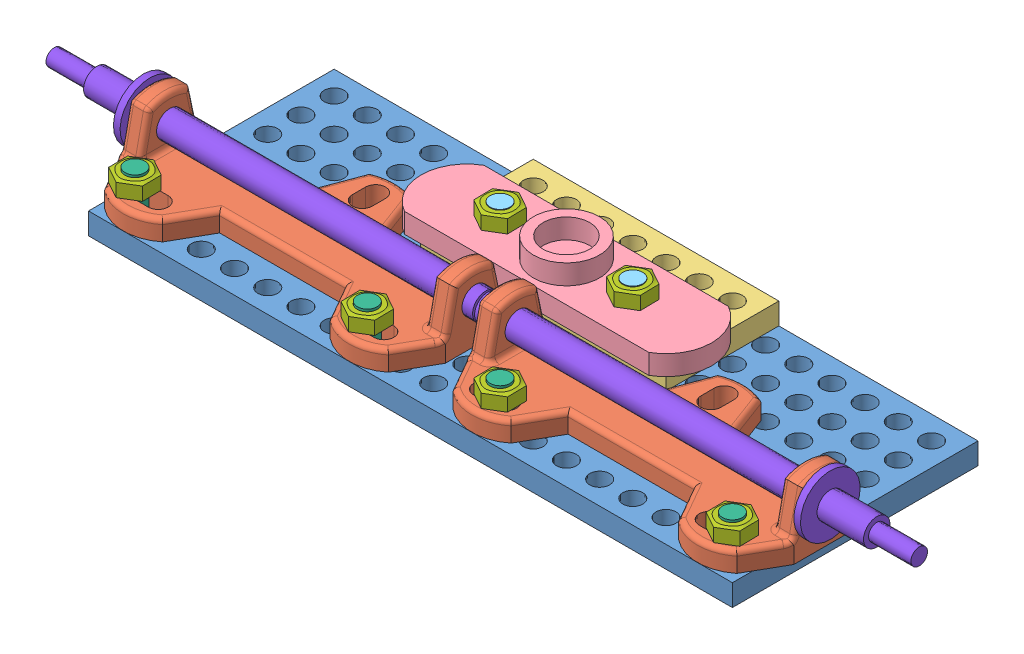
SolidWorks assembly 3, configuration Default. Lengths in mm.
Overall size (130.3 16.9 37).
19 component instances, 8 part files, 61 mates.
Components (placement in the parent):
- 3-0-1-1: 3-0-1 [Default] at (0 -9.5 5) size (97 3.25 37)
- 3-1-1-1: 3-1-1 [Default] at (14.0006 -6.25 11.4978) x (1 0 0.000071) z (-0.000071 0 1) size (49.08 10 24)
- 3-1-1-2: 3-1-1 [Default] at (-38.5006 -6.25 11.4995) x (1 0 -0.000071) z (0.000071 0 1) size (49.08 10 24)
- 3-3-1-1: 3-3-1 [Default] at (0 -6.25 -5) size (37 3.25 17)
- 3-4-1-1: 3-4-1 [Default] at (0 -3 0) size (43.8 6 12)
- 9-4-1-6: 9-4-1 [Default] at (-10 2.5 0) x (-1 0 0) z (0 0 1) size (5 13.48 5)
- 9-4-1-7: 9-4-1 [Default] at (10 2.5 0) x (1 0 0) z (0 0 -1) size (5 13.48 5)
- 9-3-1-10: 9-3-1 [Default] at (10 -0.5 20) x (1 0 0) z (0 0 -1) size (5 10.48 5)
- 9-3-1-11: 9-3-1 [Default] at (45 -0.5 20) x (1 0 0) z (0 0 -1) size (5 10.48 5)
- 9-3-1-12: 9-3-1 [Default] at (-10 -0.5 20) x (-1 0 0) z (0 0 1) size (5 10.48 5)
- 9-3-1-13: 9-3-1 [Default] at (-45 -0.5 20) x (1 0 0) z (0 0 -1) size (5 10.48 5)
- 10-1-1-4: 10-1-1 [Default] at (-10 0.2 0) size (5.11 5.14 5.85)
- 10-1-1-6: 10-1-1 [Default] at (10 0.2 0) size (5.11 5.14 5.85)
- 10-1-1-7: 10-1-1 [Default] at (-10 -3.05 20) x (1 0 -0.000071) z (0.000071 0 1) size (5.11 5.14 5.85)
- 10-1-1-8: 10-1-1 [Default] at (-45 -3.05 20) x (1 0 -0.000071) z (0.000071 0 1) size (5.11 5.14 5.85)
- 10-1-1-9: 10-1-1 [Default] at (10 -3.05 20) x (1 0 0.000071) z (-0.000071 0 1) size (5.11 5.14 5.85)
- 10-1-1-10: 10-1-1 [Default] at (45 -3.05 20) x (-1 0 -0.000071) z (0.000071 0 -1) size (5.11 5.14 5.85)
- 3-2-1-1: 3-2-1 [Default] at (65.1506 -0.25 12.0014) x (-1 0 -0.000071) z (-0.000068 -0.320728 0.947171) size (65 9 9)
- 3-2-1-2: 3-2-1 [Default] at (-65.1506 -0.25 12.0014) x (1 0 -0.000071) z (-0.000061 -0.513772 -0.857927) size (65 9 9)
Mates (geometry in assembly coordinates):
- Coincident1: coincident anti-aligned: plane of 3-0-1-1 through (0 -6.25 5) normal (0 1 0); plane of 3-1-1-2 through (-38.5006 -6.25 11.4995) normal (0 -1 0)
- Coincident2: coincident anti-aligned: plane of 3-0-1-1 through (0 -6.25 5) normal (0 1 0); plane of 3-1-1-1 through (14.0006 -6.25 11.4978) normal (0 -1 0)
- Coincident20: coincident anti-aligned: plane of 3-0-1-1 through (0 -6.25 5) normal (0 1 0); plane of 3-3-1-1 through (0 -6.25 -5) normal (0 -1 0)
- Coincident21: coincident anti-aligned: plane of 3-0-1-1 through (0 -9.5 5) normal (0 -1 0); plane of 9-4-1-6 through (-10 -9.5 0) normal (0 1 0)
- Concentric28: concentric aligned: cylinder of 3-0-1-1 through (-15 -6.25 -10) axis (0 -1 0) radius 1.5025; cylinder of 3-3-1-1 through (-15 -3 -10) axis (0 -1 0) radius 1.5025
- Concentric29: concentric anti-aligned: cylinder of 3-0-1-1 through (-10 -6.25 0) axis (0 -1 0) radius 1.5025; cylinder of 9-4-1-6 through (-10 -9.5 0) axis (0 1 0) radius 1.5
- Concentric30: concentric anti-aligned: cylinder of 3-0-1-1 through (10 -6.25 0) axis (0 -1 0) radius 1.5025; cylinder of 9-4-1-7 through (10 -9.5 0) axis (0 1 0) radius 1.5
- Coincident25: coincident anti-aligned: plane of 3-0-1-1 through (0 -9.5 5) normal (0 -1 0); plane of 9-4-1-7 through (10 -9.5 0) normal (0 1 0)
- Coincident26: coincident anti-aligned: plane of 3-3-1-1 through (0 -3 -5) normal (0 1 0); plane of 3-4-1-1 through (-15.0071 -3 0) normal (0 -1 0)
- Concentric31: concentric anti-aligned: cylinder of 3-4-1-1 through (10 0 0) axis (0 -1 0) radius 1.5025; cylinder of 9-4-1-7 through (10 -9.5 0) axis (0 1 0) radius 1.5
- Concentric32: concentric anti-aligned: cylinder of 3-4-1-1 through (-10 0 0) axis (0 -1 0) radius 1.5025; cylinder of 9-4-1-6 through (-10 -9.5 0) axis (0 1 0) radius 1.5
- Concentric34: concentric anti-aligned: cylinder of 3-3-1-1 through (10 -3 0) axis (0 -1 0) radius 1.5025; cylinder of 9-4-1-7 through (10 -9.5 0) axis (0 1 0) radius 1.5
- Concentric51: concentric anti-aligned: cylinder of 3-0-1-1 through (45 -6.25 20) axis (0 -1 0) radius 1.5025; cylinder of 9-3-1-11 through (45 -9.5 20) axis (0 1 0) radius 1.5
- Concentric52: concentric anti-aligned: cylinder of 3-1-1-1 through (45 3.75 20) axis (0 -1 0) radius 1.5; cylinder of 9-3-1-11 through (45 -9.5 20) axis (0 1 0) radius 1.5
- Coincident40: coincident anti-aligned: plane of 3-0-1-1 through (0 -9.5 5) normal (0 -1 0); plane of 9-3-1-11 through (45 -9.5 20) normal (0 1 0)
- Concentric53: concentric anti-aligned: cylinder of 3-0-1-1 through (10 -6.25 20) axis (0 -1 0) radius 1.5025; cylinder of 9-3-1-10 through (10 -9.5 20) axis (0 1 0) radius 1.5
- Tangent28: tangent anti-aligned: cylinder of 3-0-1-1 through (10 -6.25 20) axis (0 -1 0) radius 1.5025; plane of 3-1-1-1 through (14.0001 3.75 18.4978) normal (-0.000071 0 1)
- Coincident41: coincident anti-aligned: plane of 3-0-1-1 through (0 -9.5 5) normal (0 -1 0); plane of 9-3-1-10 through (10 -9.5 20) normal (0 1 0)
- Concentric54: concentric anti-aligned: cylinder of 3-0-1-1 through (-45 -6.25 20) axis (0 -1 0) radius 1.5025; cylinder of 9-3-1-13 through (-45 -9.5 20) axis (0 1 0) radius 1.5
- Coincident42: coincident anti-aligned: plane of 3-0-1-1 through (0 -9.5 5) normal (0 -1 0); plane of 9-3-1-13 through (-45 -9.5 20) normal (0 1 0)
- Concentric55: concentric anti-aligned: cylinder of 3-1-1-2 through (-45 3.75 20) axis (0 -1 0) radius 1.5; cylinder of 9-3-1-13 through (-45 -9.5 20) axis (0 1 0) radius 1.5
- Tangent30: tangent anti-aligned: cylinder of 3-0-1-1 through (-10 -6.25 20) axis (0 -1 0) radius 1.5025; plane of 3-1-1-2 through (-38.5001 3.75 18.4995) normal (0.000071 0 1)
- Concentric60: concentric anti-aligned: cylinder of 3-0-1-1 through (-10 -6.25 20) axis (0 -1 0) radius 1.5025; cylinder of 9-3-1-12 through (-10 -9.5 20) axis (0 1 0) radius 1.5
- Coincident51: coincident anti-aligned: plane of 3-0-1-1 through (0 -9.5 5) normal (0 -1 0); plane of 9-3-1-12 through (-10 -9.5 20) normal (0 1 0)
- Parallel11: parallel aligned: plane of 3-0-1-1 through (0 -9.5 5) normal (1 0 0); plane of 9-3-1-11
- Parallel12: parallel aligned: plane of 3-0-1-1 through (0 -9.5 5) normal (1 0 0); plane of 9-3-1-10
- Parallel13: parallel anti-aligned: plane of 3-0-1-1 through (0 -9.5 5) normal (1 0 0); plane of 9-3-1-12
- Parallel14: parallel aligned: plane of 3-0-1-1 through (0 -9.5 5) normal (1 0 0); plane of 9-3-1-13
- Parallel15: parallel anti-aligned: plane of 3-0-1-1 through (0 -9.5 5) normal (1 0 0); plane of 9-4-1-6
- Parallel16: parallel aligned: plane of 3-0-1-1 through (0 -9.5 5) normal (1 0 0); plane of 9-4-1-7
- Concentric66: concentric aligned: cylinder of 9-3-1-11 through (45 -9.5 20) axis (0 1 0) radius 1.5; cylinder of 10-1-1-10 through (45 -4.6196 20) axis (0 1 0) radius 1.5025
- Coincident69: coincident anti-aligned: plane of 3-1-1-1 through (1.7506 -3.25 11.4969) normal (0 1 0); plane of 10-1-1-10 through (45 -3.25 20) normal (0 -1 0)
- Parallel20: parallel anti-aligned: plane of 3-1-1-1 through (14.0006 -6.25 11.4978) normal (1 0 0.000071); plane of 10-1-1-10 through (45 -3.05 20) normal (-1 0 -0.000071)
- Concentric67: concentric aligned: cylinder of 9-3-1-10 through (10 -9.5 20) axis (0 1 0) radius 1.5; cylinder of 10-1-1-9 through (10 -4.6196 20) axis (0 1 0) radius 1.5025
- Coincident71: coincident anti-aligned: plane of 3-1-1-1 through (1.7506 -3.25 11.4969) normal (0 1 0); plane of 10-1-1-9 through (10 -3.25 20) normal (0 -1 0)
- Parallel21: parallel aligned: plane of 3-1-1-1 through (14.0006 -6.25 11.4978) normal (1 0 0.000071); plane of 10-1-1-9 through (10 -3.05 20) normal (1 0 0.000071)
- Concentric68: concentric aligned: cylinder of 9-3-1-12 through (-10 -9.5 20) axis (0 1 0) radius 1.5; cylinder of 10-1-1-7 through (-10 -4.6196 20) axis (0 1 0) radius 1.5025
- Coincident73: coincident anti-aligned: plane of 3-1-1-2 through (-50.7506 -3.25 11.5004) normal (0 1 0); plane of 10-1-1-7 through (-10 -3.25 20) normal (0 -1 0)
- Parallel22: parallel aligned: plane of 3-1-1-2 through (-38.5006 -6.25 11.4995) normal (1 0 -0.000071); plane of 10-1-1-7 through (-10 -3.05 20) normal (1 0 -0.000071)
- Concentric69: concentric aligned: cylinder of 9-3-1-13 through (-45 -9.5 20) axis (0 1 0) radius 1.5; cylinder of 10-1-1-8 through (-45 -4.6196 20) axis (0 1 0) radius 1.5025
- Coincident75: coincident anti-aligned: plane of 3-1-1-2 through (-50.7506 -3.25 11.5004) normal (0 1 0); plane of 10-1-1-8 through (-45 -3.25 20) normal (0 -1 0)
- Parallel23: parallel aligned: plane of 3-1-1-2 through (-38.5006 -6.25 11.4995) normal (1 0 -0.000071); plane of 10-1-1-8 through (-45 -3.05 20) normal (1 0 -0.000071)
- Concentric72: concentric aligned: cylinder of 9-4-1-7 through (10 -9.5 0) axis (0 1 0) radius 1.5; cylinder of 10-1-1-6 through (10 -1.3696 0) axis (0 1 0) radius 1.5025
- Coincident81: coincident anti-aligned: plane of 3-4-1-1 through (-15.0071 0 0) normal (0 1 0); plane of 10-1-1-6 through (10 0 0) normal (0 -1 0)
- Parallel26: parallel aligned: plane of 3-4-1-1 through (0 -3 0) normal (1 0 0); plane of 10-1-1-6 through (10 0.2 0) normal (1 0 0)
- Concentric73: concentric aligned: cylinder of 9-4-1-6 through (-10 -9.5 0) axis (0 1 0) radius 1.5; cylinder of 10-1-1-4 through (-10 -1.3696 0) axis (0 1 0) radius 1.5025
- Coincident83: coincident anti-aligned: plane of 3-4-1-1 through (-15.0071 0 0) normal (0 1 0); plane of 10-1-1-4 through (-10 0 0) normal (0 -1 0)
- Parallel27: parallel aligned: plane of 3-4-1-1 through (0 -3 0) normal (1 0 0); plane of 10-1-1-4 through (-10 0.2 0) normal (1 0 0)
- Concentric76: concentric aligned: cylinder of 3-1-1-1 through (1.7506 -0.25 11.9969) axis (1 0 0.000071) radius 2.0025; cylinder of 3-2-1-1 through (0.1506 -0.25 11.9968) axis (1 0 0.000071) radius 2
- Coincident88: coincident anti-aligned: plane of 3-1-1-1 through (50.7506 3.75 11.5004) normal (1 0 0.000071); plane of 3-2-1-1 through (50.7506 -0.25 12.0004) normal (-1 0 -0.000071)
- Concentric77: concentric anti-aligned: cylinder of 3-1-1-2 through (-50.7506 -0.25 12.0004) axis (1 0 -0.000071) radius 2.0025; cylinder of 3-2-1-2 through (-0.1506 -0.25 11.9968) axis (-1 0 0.000071) radius 2
- Coincident89: coincident anti-aligned: plane of 3-1-1-2 through (-50.7506 3.75 11.5004) normal (-1 0 0.000071); plane of 3-2-1-2 through (-50.7506 -0.25 12.0004) normal (1 0 -0.000071)
- Concentric79: concentric anti-aligned: cylinder of 3-2-1-2 through (-27.2615 51.691 82.0085) axis (-1 0 0.000071) radius 1.25; cylinder of ? through (-30.4615 51.691 82.0087) axis (1 0 -0.000071) radius 1.2525
- Coincident92: coincident anti-aligned: plane of 3-2-1-2 through (-27.2615 51.691 82.0085) normal (-1 0 0.000071); plane of ? through (-27.2615 51.691 82.0085) normal (1 0 -0.000071)
- Concentric80: concentric anti-aligned: cylinder of 3-2-1-1 through (90.2397 51.691 82.0085) axis (1 0 0.000071) radius 1.25; cylinder of ? through (93.4397 51.691 82.0087) axis (-1 0 -0.000071) radius 1.2525
- Coincident93: coincident anti-aligned: plane of 3-2-1-1 through (90.2397 51.691 82.0085) normal (1 0 0.000071); plane of ? through (90.2397 51.691 82.0085) normal (-1 0 -0.000071)
- Coincident95: coincident anti-aligned: plane of 3-2-1-2 through (-33.6615 51.691 82.0089) normal (-0.000061 -0.513772 -0.857927); plane of ? through (-30.4615 51.691 82.0087) normal (0.000061 0.513772 0.857927)
- Coincident96: coincident aligned: plane of 3-2-1-1 through (96.6397 51.691 82.0089) normal (-0.000068 -0.320728 0.947171); plane of ? through (93.4397 51.691 82.0087) normal (-0.000068 -0.320728 0.947171)
- Coincident97: coincident aligned: plane of 3-2-1-2 through (-33.6615 51.691 82.0089) normal (-1 0 0.000071); plane of ? through (-33.6615 51.691 82.0089) normal (-1 0 0.000071)
- Coincident98: coincident aligned: plane of 3-2-1-1 through (96.6397 51.691 82.0089) normal (1 0 0.000071); plane of ? through (96.6397 51.691 82.0089) normal (1 0 0.000071)
- Coincident102: coincident: point of 3-4-1-1; point of assembly
